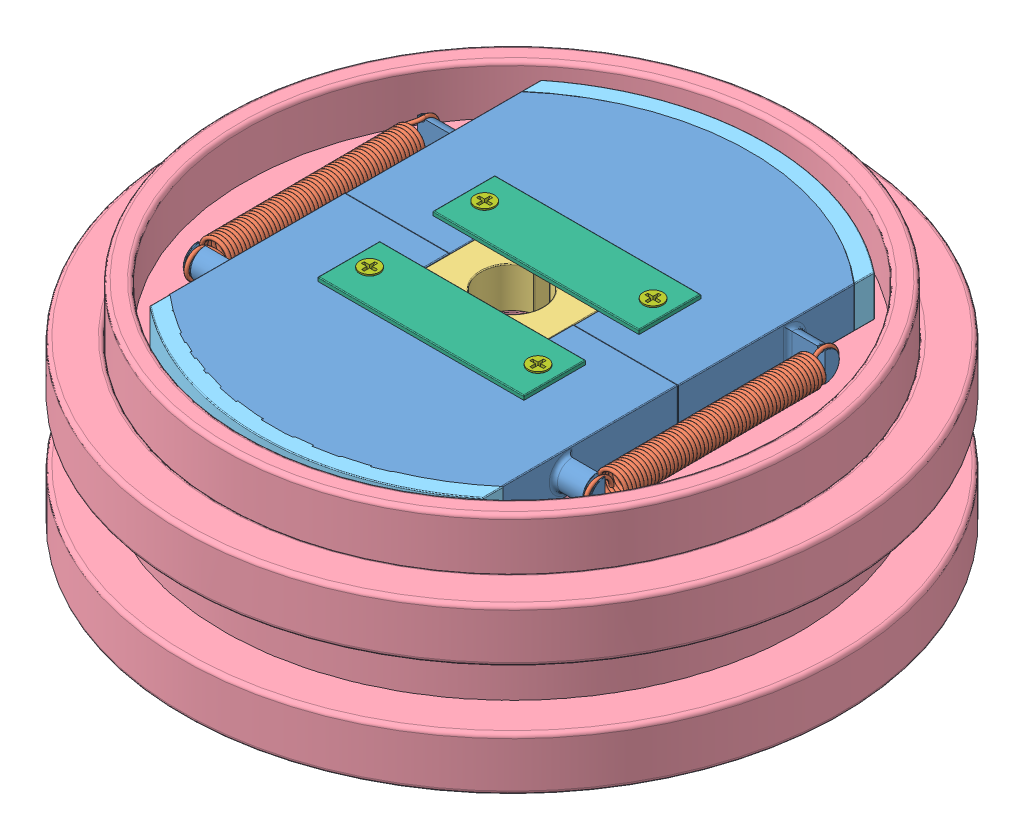
SolidWorks assembly Assem1, configuration Default. Lengths in mm.
Overall size (272.69 66.04 272.69).
14 component instances, 7 part files, 19 mates.
Components (placement in the parent):
- Proj3-SHOE-1: Proj3-SHOE [Default] at (51.18 109.6411 166.545) size (125.59 12.8 73.64)
- 9044K265_MUSIC-WIRE STL EXTENSION SPRING-1: 9044K265_MUSIC-WIRE STL EXTENSION SPRING [9044K265] at (-10.3221 116.0432 162.3092) x (0 0.005393 -0.999985) z (1 0 0) size (78.49 10.66 10.66)
- 9044K265_MUSIC-WIRE STL EXTENSION SPRING-3: 9044K265_MUSIC-WIRE STL EXTENSION SPRING [9044K265] at (112.7284 116.0896 162.3094) x (0 -0.005393 0.999985) z (1 0 0) size (78.49 10.66 10.66)
- Middle Block-1: Middle Block [Default] at (32.13 122.3411 176.365) x (1 0 0) z (0 1 0) size (38.1 28.45 12.7)
- Clutch-1: Clutch [Default] at (51.18 109.6411 162.141) x (-0.447932 0 0.894068) z (0 1 0) size (203.2 203.2 66.04)
- Proj3-LINING-3: Proj3-LINING [Default] at (51.18 109.6411 166.4132) size (102.73 12.7 24.1)
- Proj3-LINING-4: Proj3-LINING [Default] at (51.18 122.3411 157.7728) x (1 0 0) z (0 0 -1) size (102.73 12.7 24.1)
- Proj3-PLATE (1)-1: Proj3-PLATE (1) [Default] at (51.18 122.3411 166.545) size (63.5 1.27 19.05)
- flat head 100 screw_ai-4: flat head 100 screw_ai [CR-FHM1 0.138-32x0.188x0.188-N] at (77.1462 124.1826 144.615) x (0 -1 0) z (0 0 1) size (4.78 6.05 6.05)
- flat head 100 screw_ai-5: flat head 100 screw_ai [CR-FHM1 0.138-32x0.188x0.188-N] at (25.2137 124.1826 144.615) x (0 -1 0) z (0 0 -1) size (4.78 6.05 6.05)
- Proj3-SHOE-3: Proj3-SHOE [Default] at (51.0096 109.6411 157.991) x (-1 0 0) z (0 0 -1) size (125.59 12.8 73.64)
- Proj3-PLATE (1)-2: Proj3-PLATE (1) [Default] at (51.0096 122.3411 201.851) size (63.5 1.27 19.05)
- flat head 100 screw_ai-6: flat head 100 screw_ai [CR-FHM1 0.138-32x0.188x0.188-N] at (25.0434 124.1826 179.921) x (0 -1 0) z (0 0 1) size (4.78 6.05 6.05)
- flat head 100 screw_ai-7: flat head 100 screw_ai [CR-FHM1 0.138-32x0.188x0.188-N] at (76.9758 124.1826 179.921) x (0 -1 0) z (0 0 1) size (4.78 6.05 6.05)
Mates (geometry in assembly coordinates):
- Parallel12: parallel aligned: plane of Proj3-SHOE-1 through (-10.3107 109.6411 166.545) normal (1 0 0); plane of 9044K265_MUSIC-WIRE STL EXTENSION SPRING-1 through (-10.3221 116.0432 162.3092) normal (1 0 0)
- Coincident22: coincident anti-aligned: plane of Proj3-SHOE-1 through (70.23 122.3411 152.2575) normal (-1 0 0); plane of Middle Block-1 through (70.23 109.6411 176.365) normal (1 0 0)
- Coincident23: coincident aligned: plane of Proj3-SHOE-1 through (51.18 109.6411 166.545) normal (0 -1 0); plane of Middle Block-1 through (32.13 109.6411 176.365) normal (0 -1 0)
- Coincident28: coincident anti-aligned: plane of Proj3-SHOE-1 through (51.18 109.6411 166.545) normal (0 -1 0); plane of Clutch-1 through (51.18 109.6411 162.141) normal (0 1 0)
- Coincident29: coincident aligned: plane of Proj3-SHOE-1 through (51.18 122.3411 166.545) normal (0 1 0); plane of Proj3-LINING-3 through (51.18 122.3411 166.4132) normal (0 1 0)
- Coincident30: coincident aligned: plane of Proj3-SHOE-1 through (102.5462 122.3411 162.395) normal (1 0 0); plane of Proj3-LINING-3 through (102.5462 122.3411 162.2632) normal (1 0 0)
- Concentric13: concentric anti-aligned: circle of Middle Block-1; circle of Clutch-1
- Coincident32: coincident anti-aligned: plane of Proj3-SHOE-1 through (51.18 122.3411 166.545) normal (0 1 0); plane of Proj3-PLATE (1)-1 through (51.18 122.3411 166.545) normal (0 -1 0)
- Concentric15: concentric aligned: circle of Proj3-SHOE-1; circle of Proj3-PLATE (1)-1
- Concentric16: concentric anti-aligned: circle of Proj3-SHOE-1; circle of Proj3-PLATE (1)-1
- Coincident35: coincident aligned: cone of Proj3-PLATE (1)-1 through (77.1462 123.6111 144.615) axis (0 -1 0); cone of flat head 100 screw_ai-4 through (77.1462 123.7496 144.615) axis (0 -1 0)
- Coincident36: coincident aligned: cone of Proj3-PLATE (1)-1 through (25.2137 123.6111 144.615) axis (0 -1 0); cone of flat head 100 screw_ai-5 through (25.2137 123.7496 144.615) axis (0 -1 0)
- Coincident37: coincident anti-aligned: plane of Clutch-1 through (51.18 109.6411 162.141) normal (0 1 0); plane of Proj3-SHOE-3 through (51.0096 109.6411 157.991) normal (0 -1 0)
- Coincident38: coincident anti-aligned: plane of Middle Block-1 through (32.13 109.6411 176.365) normal (0 0 1); plane of Proj3-SHOE-3 through (31.9596 122.3411 176.365) normal (0 0 -1)
- Coincident39: coincident anti-aligned: plane of Proj3-SHOE-3 through (51.0096 122.3411 157.991) normal (0 1 0); plane of Proj3-PLATE (1)-2 through (51.0096 122.3411 201.851) normal (0 -1 0)
- Concentric17: concentric anti-aligned: circle of Proj3-SHOE-3; circle of Proj3-PLATE (1)-2
- Coincident40: coincident aligned: cone of Proj3-PLATE (1)-2 through (25.0434 123.6111 179.921) axis (0 -1 0); cone of flat head 100 screw_ai-6 through (25.0434 123.7496 179.921) axis (0 -1 0)
- Coincident41: coincident aligned: cone of Proj3-PLATE (1)-2 through (76.9758 123.6111 179.921) axis (0 -1 0); cone of flat head 100 screw_ai-7 through (76.9758 123.7496 179.921) axis (0 -1 0)
- Parallel13: parallel aligned: plane of Proj3-SHOE-1 through (-0.1863 122.3411 162.395) normal (-1 0 0); plane of Proj3-SHOE-3 through (-0.3566 122.3411 162.141) normal (-1 0 0)
